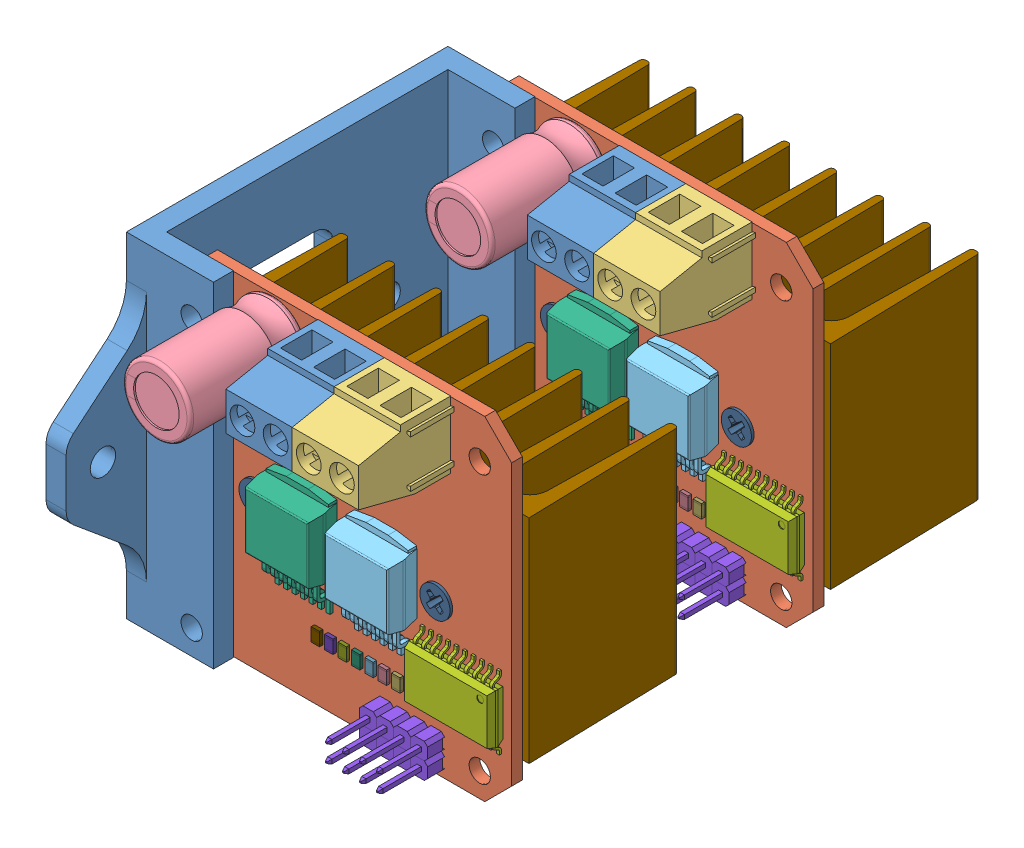
SolidWorks assembly HBridge Assembly, configuration Default. Lengths in mm.
Overall size (55.5 50 87).
43 component instances, 19 part files, 6 mates.
Components (placement in the parent):
- BTS7960 H-Bridge Module-1: BTS7960 H-Bridge Module [Default] at (-3.9323 23.7652 53.8628) size (51.5 49.9 42)
  - BTS7960 H-Bridge Module.step-1: BTS7960 H-Bridge Module.step [Default] at origin size (51.5 49.9 42)
    - 2Pos Terminal Block_001.step-1: 2Pos Terminal Block_001.step [Default] at (0.8 20 1.6) x (0 1 0) z (0 0 1) size (10 10.4 16.75)
    - Body_001.step-1: Body_001.step [Default] at origin size (49.5 49.8 1.6)
    - 2Pos Terminal Block_002.step-1: 2Pos Terminal Block_002.step [Default] at (10.7 20 1.6) x (0 1 0) z (0 0 1) size (10 10.4 16.75)
    - Capacitor_001.step-1: Capacitor_001.step [Default] at (-10.7672 19.837 1.6) x (0 -1 0) z (-1 0 0) size (10.12 17.5 10.12)
    - BTN7960_001.step-1: BTN7960_001.step [Default] at (5.9321 -1.893 1.6) size (10 15.38 4.4)
    - BTN7960_002.step-1: BTN7960_002.step [Default] at (-5.9827 -1.8968 1.6) size (10 15.38 4.4)
    - SOJ 20_001.step-1: SOJ 20_001.step [Default] at (17.2939 -12.0721 1.6) x (0 -1 0) z (0 0 1) size (10.85 12.9 2.4)
    - 2x4 Male Header_001.step-1: 2x4 Male Header_001.step [Default] at (5.8669 -22.8725 1.6) size (10.16 5.08 11.3)
    - Fillet.step-1: Fillet.step [Default] at origin size (51.5 31.77 22.9)
    - M2.5x6-Screw.step-1: M2.5x6-Screw.step [Default] at (-13.3 -2.4 2) size (4.5 4.5 6)
    - M2.5x6-Screw.step-2: M2.5x6-Screw.step [Default] at (13.7 -2.4 2) size (4.5 4.5 6)
    - 0805 Resistor_001.step-1: 0805 Resistor_001.step [Default] at (9.9588 -15.7217 1.6) x (0 -1 0) z (0 0 1) size (2 1.25 0.5)
    - 0805 Resistor_002.step-1: 0805 Resistor_002.step [Default] at (7.9588 -15.7217 1.6) x (0 -1 0) z (0 0 1) size (2 1.25 0.5)
    - 0805 Resistor_003.step-1: 0805 Resistor_003.step [Default] at (5.9588 -15.7217 1.6) x (0 -1 0) z (0 0 1) size (2 1.25 0.5)
    - 0805 Resistor_004.step-1: 0805 Resistor_004.step [Default] at (3.9588 -15.7217 1.6) x (0 -1 0) z (0 0 1) size (2 1.25 0.5)
    - 0805 Resistor_005.step-1: 0805 Resistor_005.step [Default] at (1.9588 -15.7217 1.6) x (0 -1 0) z (0 0 1) size (2 1.25 0.5)
    - 0805 Resistor_006.step-1: 0805 Resistor_006.step [Default] at (-0.0412 -15.7217 1.6) x (0 -1 0) z (0 0 1) size (2 1.25 0.5)
    - 0805 Resistor_007.step-1: 0805 Resistor_007.step [Default] at (-2.0412 -15.7217 1.6) x (0 -1 0) z (0 0 1) size (2 1.25 0.5)
    - 0805 Resistor_008.step-1: 0805 Resistor_008.step [Default] at (-4.0412 -15.7217 1.6) x (0 -1 0) z (0 0 1) size (2 1.25 0.5)
- BTS7960 H-Bridge Module-2: BTS7960 H-Bridge Module [Default] at (-3.9323 23.7652 8.8628) size (51.5 49.9 42)
  - BTS7960 H-Bridge Module.step-1: BTS7960 H-Bridge Module.step [Default] at origin size (51.5 49.9 42)
    - 2Pos Terminal Block_001.step-1: 2Pos Terminal Block_001.step [Default] at (0.8 20 1.6) x (0 1 0) z (0 0 1) size (10 10.4 16.75)
    - Body_001.step-1: Body_001.step [Default] at origin size (49.5 49.8 1.6)
    - 2Pos Terminal Block_002.step-1: 2Pos Terminal Block_002.step [Default] at (10.7 20 1.6) x (0 1 0) z (0 0 1) size (10 10.4 16.75)
    - Capacitor_001.step-1: Capacitor_001.step [Default] at (-10.7672 19.837 1.6) x (0 -1 0) z (-1 0 0) size (10.12 17.5 10.12)
    - BTN7960_001.step-1: BTN7960_001.step [Default] at (5.9321 -1.893 1.6) size (10 15.38 4.4)
    - BTN7960_002.step-1: BTN7960_002.step [Default] at (-5.9827 -1.8968 1.6) size (10 15.38 4.4)
    - SOJ 20_001.step-1: SOJ 20_001.step [Default] at (17.2939 -12.0721 1.6) x (0 -1 0) z (0 0 1) size (10.85 12.9 2.4)
    - 2x4 Male Header_001.step-1: 2x4 Male Header_001.step [Default] at (5.8669 -22.8725 1.6) size (10.16 5.08 11.3)
    - Fillet.step-1: Fillet.step [Default] at origin size (51.5 31.77 22.9)
    - M2.5x6-Screw.step-1: M2.5x6-Screw.step [Default] at (-13.3 -2.4 2) size (4.5 4.5 6)
    - M2.5x6-Screw.step-2: M2.5x6-Screw.step [Default] at (13.7 -2.4 2) size (4.5 4.5 6)
    - 0805 Resistor_001.step-1: 0805 Resistor_001.step [Default] at (9.9588 -15.7217 1.6) x (0 -1 0) z (0 0 1) size (2 1.25 0.5)
    - 0805 Resistor_002.step-1: 0805 Resistor_002.step [Default] at (7.9588 -15.7217 1.6) x (0 -1 0) z (0 0 1) size (2 1.25 0.5)
    - 0805 Resistor_003.step-1: 0805 Resistor_003.step [Default] at (5.9588 -15.7217 1.6) x (0 -1 0) z (0 0 1) size (2 1.25 0.5)
    - 0805 Resistor_004.step-1: 0805 Resistor_004.step [Default] at (3.9588 -15.7217 1.6) x (0 -1 0) z (0 0 1) size (2 1.25 0.5)
    - 0805 Resistor_005.step-1: 0805 Resistor_005.step [Default] at (1.9588 -15.7217 1.6) x (0 -1 0) z (0 0 1) size (2 1.25 0.5)
    - 0805 Resistor_006.step-1: 0805 Resistor_006.step [Default] at (-0.0412 -15.7217 1.6) x (0 -1 0) z (0 0 1) size (2 1.25 0.5)
    - 0805 Resistor_007.step-1: 0805 Resistor_007.step [Default] at (-2.0412 -15.7217 1.6) x (0 -1 0) z (0 0 1) size (2 1.25 0.5)
    - 0805 Resistor_008.step-1: 0805 Resistor_008.step [Default] at (-4.0412 -15.7217 1.6) x (0 -1 0) z (0 0 1) size (2 1.25 0.5)
- H Bridge mount-1: H Bridge mount [Default] at (-33.6823 -1.2348 58.4628) size (13 50 60)
Mates (geometry in assembly coordinates):
- Coincident1: coincident anti-aligned: plane of BTS7960 H-Bridge Module-1/BTS7960 H-Bridge Module.step-1/Body_001.step-1 through (-3.9323 23.7652 55.4628) normal (0 0 1); plane of H Bridge mount-1 through (-30.6823 48.7652 55.4628) normal (0 0 -1)
- Width1: width anti-aligned: plane of BTS7960 H-Bridge Module-1/BTS7960 H-Bridge Module.step-1/Body_001.step-1 through (-28.6823 48.6652 53.8628) normal (0 1 0); plane of H Bridge mount-1 through (20.8177 -1.1348 53.8628) normal (0 -1 0); plane of BTS7960 H-Bridge Module-1/BTS7960 H-Bridge Module.step-1/Body_001.step-1 through (-33.6823 -1.2348 58.4628) normal (0 -1 0); plane of H Bridge mount-1 through (-33.6823 48.7652 58.4628) normal (0 1 0)
- Width2: width anti-aligned: plane of BTS7960 H-Bridge Module-2/BTS7960 H-Bridge Module.step-1/Body_001.step-1 through (-28.6823 48.6652 8.8628) normal (0 1 0); plane of H Bridge mount-1 through (20.8177 -1.1348 8.8628) normal (0 -1 0); plane of BTS7960 H-Bridge Module-2/BTS7960 H-Bridge Module.step-1/Body_001.step-1 through (-33.6823 -1.2348 58.4628) normal (0 -1 0); plane of H Bridge mount-1 through (-33.6823 48.7652 58.4628) normal (0 1 0)
- Coincident2: coincident anti-aligned: plane of BTS7960 H-Bridge Module-2/BTS7960 H-Bridge Module.step-1/Body_001.step-1 through (-3.9323 23.7652 10.4628) normal (0 0 1); plane of H Bridge mount-1 through (-33.6823 48.7652 10.4628) normal (0 0 -1)
- Distance2: distance = 1 mm: line of BTS7960 H-Bridge Module-2/BTS7960 H-Bridge Module.step-1/Fillet.step-1 through (-29.6823 5.4802 8.8628) axis (0 1 0); plane of H Bridge mount-1 through (-30.6823 48.7652 13.4628) normal (1 0 0)
- Distance1: distance = 1 mm: line of BTS7960 H-Bridge Module-1/BTS7960 H-Bridge Module.step-1/Fillet.step-1 through (-29.6823 5.4802 53.8628) axis (0 1 0); plane of H Bridge mount-1 through (-30.6823 48.7652 13.4628) normal (1 0 0)
